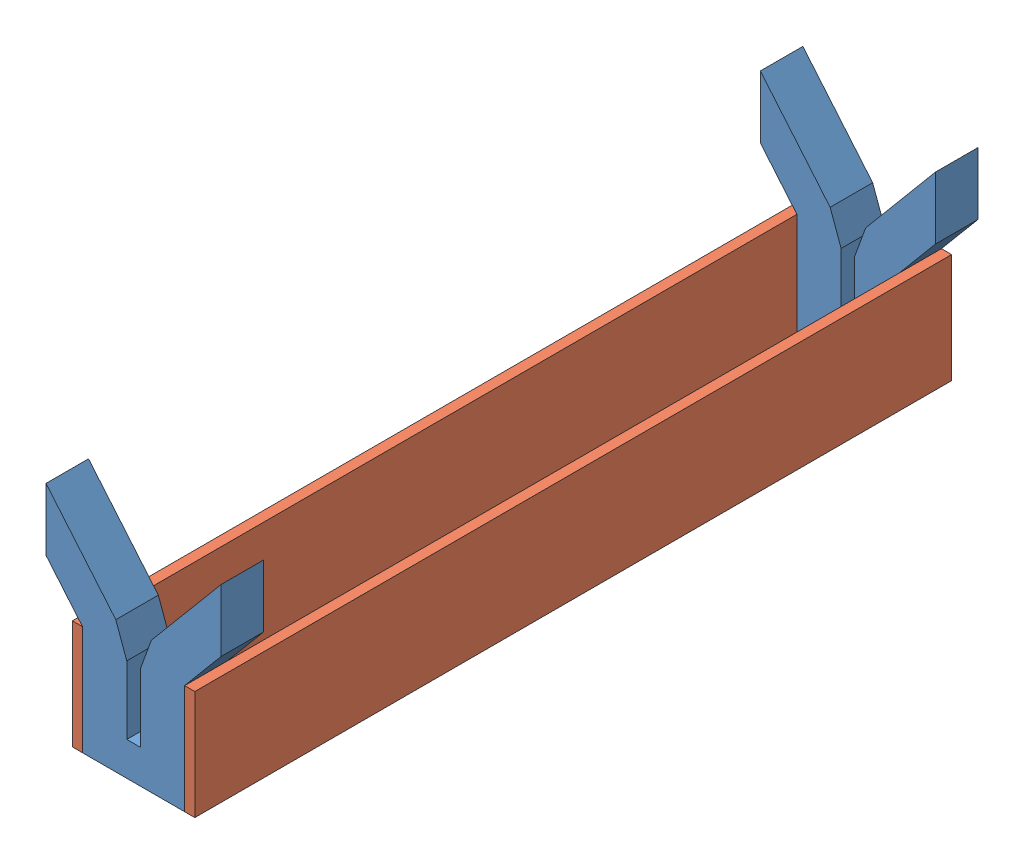
SolidWorks assembly Assem1, configuration Default. Lengths in mm.
Overall size (51.49 63.23 222.5).
4 component instances, 2 part files, 9 mates.
Components (placement in the parent):
- gripper-1: gripper [Default] at (22.3165 16.7858 60.225) size (51.49 63.23 12.5)
- gripper-2: gripper [Default] at (22.3165 16.7858 -149.775) size (51.49 63.23 12.5)
- p-1: p [Default] at (40.3165 48.8858 -149.775) x (0 0 -1) z (0 1 0) size (222.5 3 32.1)
- p-2: p [Default] at (4.3165 16.7858 -149.775) x (0 0 -1) z (0 -1 0) size (222.5 3 32.1)
Mates (geometry in assembly coordinates):
- Coincident1: coincident aligned: plane of gripper-1 through (37.3165 16.7858 72.725) normal (1 0 0); plane of gripper-2 through (37.3165 16.7858 -137.275) normal (1 0 0)
- Coincident2: coincident aligned: plane of gripper-1 through (22.3165 16.7858 72.725) normal (0 -1 0); plane of gripper-2 through (22.3165 16.7858 -137.275) normal (0 -1 0)
- Distance1: distance = 210 mm aligned: plane of gripper-1 through (22.3165 16.7858 60.225) normal (0 0 -1); plane of gripper-2 through (22.3165 16.7858 -149.775) normal (0 0 -1)
- Coincident4: coincident: plane of gripper-1 through (7.3165 16.7858 72.725) normal (-1 0 0); plane of p-2 through (7.3165 16.8707 -149.775) normal (1 0 0)
- Coincident5: coincident anti-aligned: plane of gripper-2 through (37.3165 16.7858 -137.275) normal (1 0 0); plane of p-1 through (37.3165 39.6753 -149.775) normal (-1 0 0)
- Coincident6: coincident: plane of gripper-1 through (22.3165 16.7858 72.725) normal (0 0 1); plane of p-2 through (7.3165 16.8707 72.725) normal (0 0 1)
- Coincident7: coincident aligned: plane of gripper-1 through (22.3165 16.7858 72.725) normal (0 0 1); plane of p-1 through (37.3165 39.6753 72.725) normal (0 0 1)
- Coincident8: coincident aligned: plane of gripper-1 through (22.3165 16.7858 72.725) normal (0 -1 0); plane of p-2 through (7.3165 16.7858 -149.775) normal (0 -1 0)
- Coincident9: coincident aligned: plane of gripper-1 through (22.3165 16.7858 72.725) normal (0 -1 0); plane of p-1 through (37.3165 16.7858 -149.775) normal (0 -1 0)
